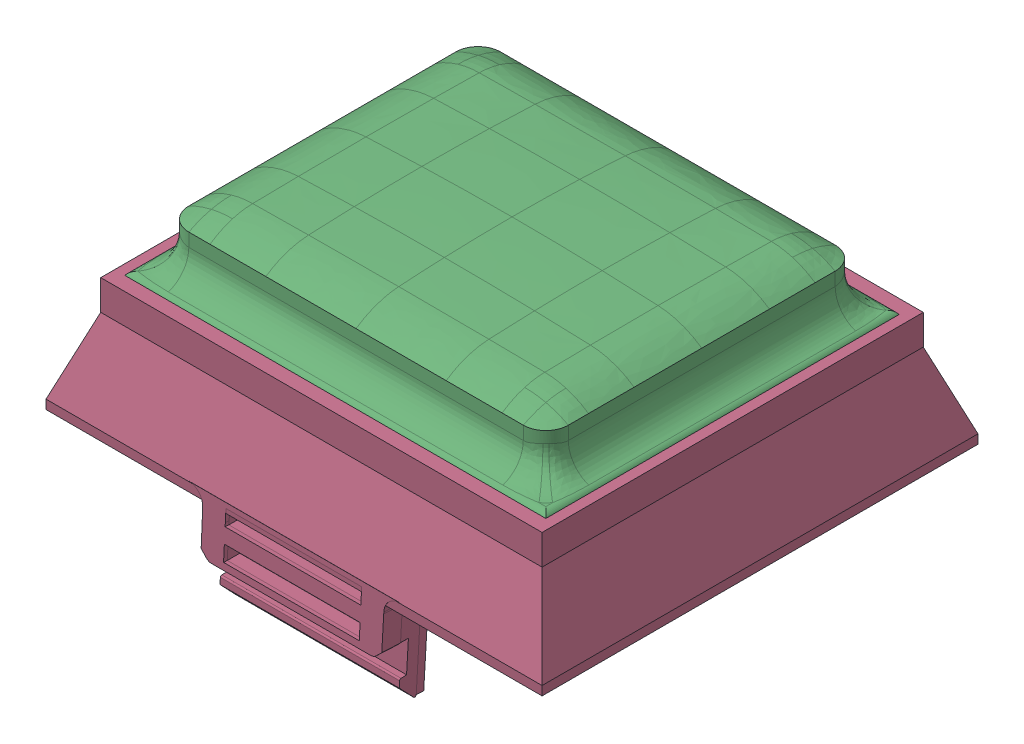
SolidWorks assembly Original, configuration 默认. Lengths in mm.
Overall size (33 18.3 29.5).
4 component instances, 4 part files, 10 mates.
Components (placement in the parent):
- lensall-1: lensall [默认] at origin size (28.33 2.18 23.83)
- InsideSkin-1: InsideSkin [默认] at (0.0001 0 0.2499) size (23.8 5.48 19.29)
- Topskin-1: Topskin [默认] at (0.0001 2 0.2499) size (28.02 6.25 23.52)
- SupportBase-2: SupportBase [默认] at origin size (33 14.05 29.5)
Mates (geometry in assembly coordinates):
- 同心2: concentric anti-aligned: cylinder of InsideSkin-1 through (10.8751 17.7531 8.6249) axis (0 1 0) radius 0.7; cylinder of Board3Con1612611OriginalSkin_TOP-1 through (10.8751 24 8.6249) axis (0 -1 0) radius 0.7
- 同心3: concentric anti-aligned: cylinder of InsideSkin-1 through (10.8751 17.7531 -9.1251) axis (0 1 0) radius 0.7; cylinder of Board3Con1612611OriginalSkin_TOP-1 through (10.8751 24 -9.1251) axis (0 -1 0) radius 0.7
- 重合4: coincident aligned: plane of InsideSkin-1 through (10.8751 19 -9.1251) normal (0 -1 0); plane of Board3Con1612611OriginalSkin_TOP-1 through (0.0001 19 0.2499) normal (0 -1 0)
- 重合6: coordinate: point of SupportBase-2
- 重合7: coincident anti-aligned: plane of lensall-1 through (13.75 19 -11.5) normal (0.939693 0.34202 0); plane of SupportBase-2 through (13.75 19 12.7803) normal (-0.939693 -0.34202 0)
- 同心5: concentric aligned: cylinder of lensall-1 through (13.3294 18.6938 -11.0794) axis (-0.323616 0.889126 0.323616) radius 0.5; cylinder of SupportBase-2 through (10.7866 25.6801 -8.5366) axis (-0.323616 0.889126 0.323616) radius 0.5
- 重合8: coincident anti-aligned: plane of lensall-1 through (0 18 0) normal (0 -1 0); plane of SupportBase-2 through (0 18 0) normal (0 1 0)
- 重合9: coincident anti-aligned: plane of lensall-1 through (0 19 0) normal (0 1 0); plane of Board3Con1612611OriginalSkin_TOP-1 through (0.0001 19 0.2499) normal (0 -1 0)
- 重合10: coincident anti-aligned: plane of Board3Con1612611OriginalSkin_TOP-1 through (0.0001 19 11.7499) normal (0 0 1); plane of SupportBase-2 through (-13.5999 21 11.7499) normal (0 0 -1)
- 重合11: coincident anti-aligned: plane of Board3Con1612611OriginalSkin_TOP-1 through (14.0001 19 0.2499) normal (1 0 0); plane of SupportBase-2 through (14.0001 21 11.7499) normal (-1 0 0)
